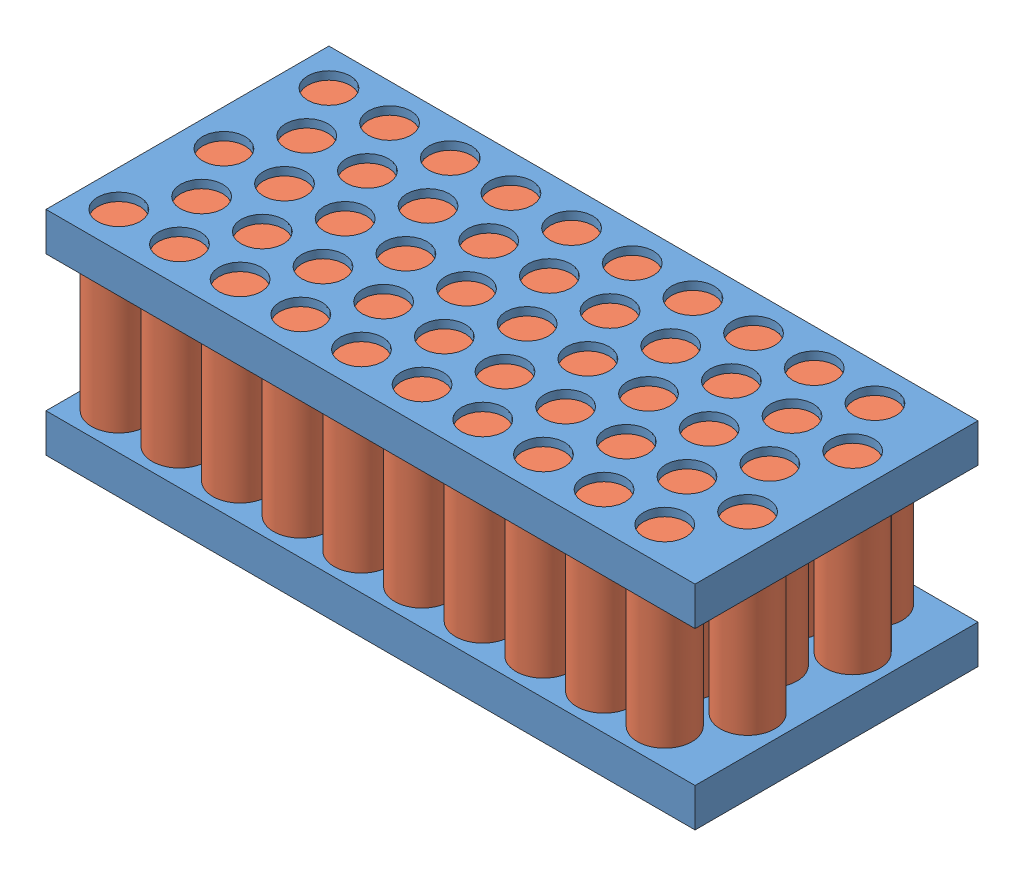
SolidWorks assembly Bank, configuration Default. Lengths in mm.
Overall size (214 70.2 93.28).
52 component instances, 2 part files, 153 mates.
Components (placement in the parent):
- EggCrate-1: EggCrate [Default] at origin size (214 12.7 93.28)
- 18650-1: 18650 [Default] at (180 10 0) x (0 0 -1) z (-1 0 0) size (18 65 18)
- 18650-2: 18650 [Default] at (160 10 0) x (0 0 -1) z (-1 0 0) size (18 65 18)
- 18650-3: 18650 [Default] at (140 10 0) x (0 0 -1) z (-1 0 0) size (18 65 18)
- 18650-4: 18650 [Default] at (120 10 0) x (0 0 -1) z (-1 0 0) size (18 65 18)
- 18650-5: 18650 [Default] at (100 10 0) x (0 0 -1) z (-1 0 0) size (18 65 18)
- 18650-6: 18650 [Default] at (80 10 0) x (0 0 -1) z (-1 0 0) size (18 65 18)
- 18650-7: 18650 [Default] at (60 10 0) x (0 0 -1) z (-1 0 0) size (18 65 18)
- 18650-8: 18650 [Default] at (40 10 0) x (0 0 -1) z (-1 0 0) size (18 65 18)
- 18650-9: 18650 [Default] at (20 10 0) x (0 0 -1) z (-1 0 0) size (18 65 18)
- 18650-10: 18650 [Default] at (0 10 0) x (0 0 -1) z (-1 0 0) size (18 65 18)
- 18650-11: 18650 [Default] at (10 10 -17.3205) x (0 0 -1) z (-1 0 0) size (18 65 18)
- 18650-12: 18650 [Default] at (30 10 -17.3205) x (0 0 -1) z (-1 0 0) size (18 65 18)
- 18650-13: 18650 [Default] at (50 10 -17.3205) x (0 0 -1) z (-1 0 0) size (18 65 18)
- 18650-14: 18650 [Default] at (70 10 -17.3205) x (0 0 -1) z (-1 0 0) size (18 65 18)
- 18650-15: 18650 [Default] at (90 10 -17.3205) x (0 0 -1) z (-1 0 0) size (18 65 18)
- 18650-16: 18650 [Default] at (110 10 -17.3205) x (0 0 -1) z (-1 0 0) size (18 65 18)
- 18650-17: 18650 [Default] at (130 10 -17.3205) x (0 0 -1) z (-1 0 0) size (18 65 18)
- 18650-18: 18650 [Default] at (150 10 -17.3205) x (0 0 -1) z (-1 0 0) size (18 65 18)
- 18650-19: 18650 [Default] at (170 10 -17.3205) x (0 0 -1) z (-1 0 0) size (18 65 18)
- 18650-20: 18650 [Default] at (190 10 -17.3205) x (0 0 -1) z (-1 0 0) size (18 65 18)
- 18650-21: 18650 [Default] at (0 10 -34.641) x (0 0 -1) z (-1 0 0) size (18 65 18)
- 18650-22: 18650 [Default] at (20 10 -34.641) x (0 0 -1) z (-1 0 0) size (18 65 18)
- 18650-23: 18650 [Default] at (40 10 -34.641) x (0 0 -1) z (-1 0 0) size (18 65 18)
- 18650-24: 18650 [Default] at (60 10 -34.641) x (0 0 -1) z (-1 0 0) size (18 65 18)
- 18650-25: 18650 [Default] at (80 10 -34.641) x (0 0 -1) z (-1 0 0) size (18 65 18)
- 18650-26: 18650 [Default] at (100 10 -34.641) x (0 0 -1) z (-1 0 0) size (18 65 18)
- 18650-27: 18650 [Default] at (120 10 -34.641) x (0 0 -1) z (-1 0 0) size (18 65 18)
- 18650-28: 18650 [Default] at (140 10 -34.641) x (0 0 -1) z (-1 0 0) size (18 65 18)
- 18650-29: 18650 [Default] at (160 10 -34.641) x (0 0 -1) z (-1 0 0) size (18 65 18)
- 18650-30: 18650 [Default] at (180 10 -34.641) x (0 0 -1) z (-1 0 0) size (18 65 18)
- 18650-31: 18650 [Default] at (10 10 -51.9615) x (0 0 -1) z (-1 0 0) size (18 65 18)
- 18650-32: 18650 [Default] at (30 10 -51.9615) x (0 0 -1) z (-1 0 0) size (18 65 18)
- 18650-33: 18650 [Default] at (50 10 -51.9615) x (0 0 -1) z (-1 0 0) size (18 65 18)
- 18650-34: 18650 [Default] at (70 10 -51.9615) x (0 0 -1) z (-1 0 0) size (18 65 18)
- 18650-35: 18650 [Default] at (90 10 -51.9615) x (0 0 -1) z (-1 0 0) size (18 65 18)
- 18650-36: 18650 [Default] at (110 10 -51.9615) x (0 0 -1) z (-1 0 0) size (18 65 18)
- 18650-37: 18650 [Default] at (130 10 -51.9615) x (0 0 -1) z (-1 0 0) size (18 65 18)
- 18650-38: 18650 [Default] at (150 10 -51.9615) x (0 0 -1) z (-1 0 0) size (18 65 18)
- 18650-39: 18650 [Default] at (170 10 -51.9615) x (0 0 -1) z (-1 0 0) size (18 65 18)
- 18650-40: 18650 [Default] at (190 10 -51.9615) x (0 0 -1) z (-1 0 0) size (18 65 18)
- 18650-41: 18650 [Default] at (180 10 -69.282) x (0 0 -1) z (-1 0 0) size (18 65 18)
- 18650-42: 18650 [Default] at (160 10 -69.282) x (0 0 -1) z (-1 0 0) size (18 65 18)
- 18650-43: 18650 [Default] at (140 10 -69.282) x (0 0 -1) z (-1 0 0) size (18 65 18)
- 18650-44: 18650 [Default] at (120 10 -69.282) x (0 0 -1) z (-1 0 0) size (18 65 18)
- 18650-45: 18650 [Default] at (100 10 -69.282) x (0 0 -1) z (-1 0 0) size (18 65 18)
- 18650-46: 18650 [Default] at (80 10 -69.282) x (0 0 -1) z (-1 0 0) size (18 65 18)
- 18650-47: 18650 [Default] at (60 10 -69.282) x (0 0 -1) z (-1 0 0) size (18 65 18)
- 18650-48: 18650 [Default] at (40 10 -69.282) x (0 0 -1) z (-1 0 0) size (18 65 18)
- 18650-49: 18650 [Default] at (20 10 -69.282) x (0 0 -1) z (-1 0 0) size (18 65 18)
- 18650-50: 18650 [Default] at (0 10 -69.282) x (0 0 -1) z (-1 0 0) size (18 65 18)
- EggCrate-2: EggCrate [Default] at (0 -44.8 -69.282) x (1 0 0) z (0 0 -1) size (214 12.7 93.28)
Mates (geometry in assembly coordinates):
- Coincident1: coincident anti-aligned: plane of EggCrate-1 through (180 10 0) normal (0 -1 0); plane of 18650-1 through (180 10 0) normal (0 1 0)
- Concentric1: concentric anti-aligned: cylinder of EggCrate-1 through (180 10 0) axis (0 -1 0) radius 9; cylinder of 18650-1 through (180 -55 0) axis (0 1 0) radius 9
- Parallel1: parallel anti-aligned: plane of 18650-1 through (180 10 0) normal (-1 0 0); plane of assembly through (0 0 0) normal (1 0 0)
- Coincident5: coincident anti-aligned: plane of EggCrate-1 through (180 10 0) normal (0 -1 0); plane of 18650-2 through (160 10 0) normal (0 1 0)
- Parallel2: parallel anti-aligned: plane of 18650-2 through (160 10 0) normal (-1 0 0); plane of assembly through (0 0 0) normal (1 0 0)
- Concentric2: concentric anti-aligned: cylinder of EggCrate-1 through (160 10 0) axis (0 -1 0) radius 9; cylinder of 18650-2 through (160 -55 0) axis (0 1 0) radius 9
- Coincident6: coincident anti-aligned: plane of EggCrate-1 through (180 10 0) normal (0 -1 0); plane of 18650-3 through (140 10 0) normal (0 1 0)
- Concentric3: concentric anti-aligned: cylinder of EggCrate-1 through (140 10 0) axis (0 -1 0) radius 9; cylinder of 18650-3 through (140 -55 0) axis (0 1 0) radius 9
- Parallel3: parallel anti-aligned: plane of 18650-3 through (140 10 0) normal (-1 0 0); plane of assembly through (0 0 0) normal (1 0 0)
- Coincident7: coincident anti-aligned: plane of EggCrate-1 through (180 10 0) normal (0 -1 0); plane of 18650-4 through (120 10 0) normal (0 1 0)
- Concentric4: concentric anti-aligned: cylinder of EggCrate-1 through (120 10 0) axis (0 -1 0) radius 9; cylinder of 18650-4 through (120 -55 0) axis (0 1 0) radius 9
- Parallel4: parallel anti-aligned: plane of 18650-4 through (120 10 0) normal (-1 0 0); plane of assembly through (0 0 0) normal (1 0 0)
- Coincident8: coincident anti-aligned: plane of EggCrate-1 through (180 10 0) normal (0 -1 0); plane of 18650-5 through (100 10 0) normal (0 1 0)
- Concentric5: concentric anti-aligned: cylinder of EggCrate-1 through (100 10 0) axis (0 -1 0) radius 9; cylinder of 18650-5 through (100 -55 0) axis (0 1 0) radius 9
- Parallel5: parallel anti-aligned: plane of 18650-5 through (100 10 0) normal (-1 0 0); plane of assembly through (0 0 0) normal (1 0 0)
- Coincident9: coincident anti-aligned: plane of EggCrate-1 through (180 10 0) normal (0 -1 0); plane of 18650-6 through (80 10 0) normal (0 1 0)
- Concentric6: concentric anti-aligned: cylinder of EggCrate-1 through (80 10 0) axis (0 -1 0) radius 9; cylinder of 18650-6 through (80 -55 0) axis (0 1 0) radius 9
- Parallel6: parallel anti-aligned: plane of 18650-6 through (80 10 0) normal (-1 0 0); plane of assembly through (0 0 0) normal (1 0 0)
- Coincident10: coincident anti-aligned: plane of EggCrate-1 through (180 10 0) normal (0 -1 0); plane of 18650-7 through (60 10 0) normal (0 1 0)
- Concentric7: concentric anti-aligned: cylinder of EggCrate-1 through (60 10 0) axis (0 -1 0) radius 9; cylinder of 18650-7 through (60 -55 0) axis (0 1 0) radius 9
- Parallel7: parallel anti-aligned: plane of 18650-7 through (60 10 0) normal (-1 0 0); plane of assembly through (0 0 0) normal (1 0 0)
- Coincident11: coincident anti-aligned: plane of EggCrate-1 through (180 10 0) normal (0 -1 0); plane of 18650-8 through (40 10 0) normal (0 1 0)
- Concentric8: concentric anti-aligned: cylinder of EggCrate-1 through (40 10 0) axis (0 -1 0) radius 9; cylinder of 18650-8 through (40 -55 0) axis (0 1 0) radius 9
- Parallel8: parallel anti-aligned: plane of 18650-8 through (40 10 0) normal (-1 0 0); plane of assembly through (0 0 0) normal (1 0 0)
- Coincident12: coincident anti-aligned: plane of EggCrate-1 through (180 10 0) normal (0 -1 0); plane of 18650-9 through (20 10 0) normal (0 1 0)
- Concentric9: concentric anti-aligned: cylinder of EggCrate-1 through (20 10 0) axis (0 -1 0) radius 9; cylinder of 18650-9 through (20 -55 0) axis (0 1 0) radius 9
- Parallel9: parallel anti-aligned: plane of 18650-9 through (20 10 0) normal (-1 0 0); plane of assembly through (0 0 0) normal (1 0 0)
- Coincident13: coincident anti-aligned: plane of EggCrate-1 through (180 10 0) normal (0 -1 0); plane of 18650-10 through (0 10 0) normal (0 1 0)
- Concentric10: concentric anti-aligned: cylinder of EggCrate-1 through (0 10 0) axis (0 -1 0) radius 9; cylinder of 18650-10 through (0 -55 0) axis (0 1 0) radius 9
- Parallel10: parallel anti-aligned: plane of 18650-10 through (0 10 0) normal (-1 0 0); plane of assembly through (0 0 0) normal (1 0 0)
- Coincident14: coincident anti-aligned: plane of EggCrate-1 through (180 10 0) normal (0 -1 0); plane of 18650-11 through (10 10 -17.3205) normal (0 1 0)
- Concentric11: concentric anti-aligned: cylinder of EggCrate-1 through (10 10 -17.3205) axis (0 -1 0) radius 9; cylinder of 18650-11 through (10 -55 -17.3205) axis (0 1 0) radius 9
- Parallel11: parallel anti-aligned: plane of 18650-11 through (10 10 -17.3205) normal (-1 0 0); plane of assembly through (0 0 0) normal (1 0 0)
- Coincident15: coincident anti-aligned: plane of EggCrate-1 through (180 10 0) normal (0 -1 0); plane of 18650-12 through (30 10 -17.3205) normal (0 1 0)
- Concentric12: concentric anti-aligned: cylinder of EggCrate-1 through (30 10 -17.3205) axis (0 -1 0) radius 9; cylinder of 18650-12 through (30 -55 -17.3205) axis (0 1 0) radius 9
- Parallel12: parallel anti-aligned: plane of 18650-12 through (30 10 -17.3205) normal (-1 0 0); plane of assembly through (0 0 0) normal (1 0 0)
- Coincident16: coincident anti-aligned: plane of EggCrate-1 through (180 10 0) normal (0 -1 0); plane of 18650-13 through (50 10 -17.3205) normal (0 1 0)
- Concentric13: concentric anti-aligned: cylinder of EggCrate-1 through (50 10 -17.3205) axis (0 -1 0) radius 9; cylinder of 18650-13 through (50 -55 -17.3205) axis (0 1 0) radius 9
- Parallel13: parallel anti-aligned: plane of 18650-13 through (50 10 -17.3205) normal (-1 0 0); plane of assembly through (0 0 0) normal (1 0 0)
- Coincident17: coincident anti-aligned: plane of EggCrate-1 through (180 10 0) normal (0 -1 0); plane of 18650-14 through (70 10 -17.3205) normal (0 1 0)
- Concentric14: concentric anti-aligned: cylinder of EggCrate-1 through (70 10 -17.3205) axis (0 -1 0) radius 9; cylinder of 18650-14 through (70 -55 -17.3205) axis (0 1 0) radius 9
- Parallel14: parallel anti-aligned: plane of 18650-14 through (70 10 -17.3205) normal (-1 0 0); plane of assembly through (0 0 0) normal (1 0 0)
- Coincident18: coincident anti-aligned: plane of EggCrate-1 through (180 10 0) normal (0 -1 0); plane of 18650-15 through (90 10 -17.3205) normal (0 1 0)
- Concentric15: concentric anti-aligned: cylinder of EggCrate-1 through (90 10 -17.3205) axis (0 -1 0) radius 9; cylinder of 18650-15 through (90 -55 -17.3205) axis (0 1 0) radius 9
- Parallel15: parallel anti-aligned: plane of 18650-15 through (90 10 -17.3205) normal (-1 0 0); plane of assembly through (0 0 0) normal (1 0 0)
- Coincident19: coincident anti-aligned: plane of EggCrate-1 through (180 10 0) normal (0 -1 0); plane of 18650-16 through (110 10 -17.3205) normal (0 1 0)
- Concentric16: concentric anti-aligned: cylinder of EggCrate-1 through (110 10 -17.3205) axis (0 -1 0) radius 9; cylinder of 18650-16 through (110 -55 -17.3205) axis (0 1 0) radius 9
- Parallel16: parallel anti-aligned: plane of 18650-16 through (110 10 -17.3205) normal (-1 0 0); plane of assembly through (0 0 0) normal (1 0 0)
- Coincident20: coincident anti-aligned: plane of EggCrate-1 through (180 10 0) normal (0 -1 0); plane of 18650-17 through (130 10 -17.3205) normal (0 1 0)
- Concentric17: concentric anti-aligned: cylinder of EggCrate-1 through (130 10 -17.3205) axis (0 -1 0) radius 9; cylinder of 18650-17 through (130 -55 -17.3205) axis (0 1 0) radius 9
- Parallel17: parallel anti-aligned: plane of 18650-17 through (130 10 -17.3205) normal (-1 0 0); plane of assembly through (0 0 0) normal (1 0 0)
- Coincident21: coincident anti-aligned: plane of EggCrate-1 through (180 10 0) normal (0 -1 0); plane of 18650-18 through (150 10 -17.3205) normal (0 1 0)
- Concentric18: concentric anti-aligned: cylinder of EggCrate-1 through (150 10 -17.3205) axis (0 -1 0) radius 9; cylinder of 18650-18 through (150 -55 -17.3205) axis (0 1 0) radius 9
- Parallel18: parallel anti-aligned: plane of 18650-18 through (150 10 -17.3205) normal (-1 0 0); plane of assembly through (0 0 0) normal (1 0 0)
- Coincident22: coincident anti-aligned: plane of EggCrate-1 through (180 10 0) normal (0 -1 0); plane of 18650-19 through (170 10 -17.3205) normal (0 1 0)
- Concentric19: concentric anti-aligned: cylinder of EggCrate-1 through (170 10 -17.3205) axis (0 -1 0) radius 9; cylinder of 18650-19 through (170 -55 -17.3205) axis (0 1 0) radius 9
- Parallel19: parallel anti-aligned: plane of 18650-19 through (170 10 -17.3205) normal (-1 0 0); plane of assembly through (0 0 0) normal (1 0 0)
- Coincident23: coincident anti-aligned: plane of EggCrate-1 through (180 10 0) normal (0 -1 0); plane of 18650-20 through (190 10 -17.3205) normal (0 1 0)
- Concentric20: concentric anti-aligned: cylinder of EggCrate-1 through (190 10 -17.3205) axis (0 -1 0) radius 9; cylinder of 18650-20 through (190 -55 -17.3205) axis (0 1 0) radius 9
- Parallel20: parallel anti-aligned: plane of 18650-20 through (190 10 -17.3205) normal (-1 0 0); plane of assembly through (0 0 0) normal (1 0 0)
- Coincident24: coincident anti-aligned: plane of EggCrate-1 through (180 10 0) normal (0 -1 0); plane of 18650-21 through (0 10 -34.641) normal (0 1 0)
- Concentric21: concentric anti-aligned: cylinder of EggCrate-1 through (0 10 -34.641) axis (0 -1 0) radius 9; cylinder of 18650-21 through (0 -55 -34.641) axis (0 1 0) radius 9
- Parallel21: parallel anti-aligned: plane of 18650-21 through (0 10 -34.641) normal (-1 0 0); plane of assembly through (0 0 0) normal (1 0 0)
- Coincident25: coincident anti-aligned: plane of EggCrate-1 through (180 10 0) normal (0 -1 0); plane of 18650-22 through (20 10 -34.641) normal (0 1 0)
- Concentric22: concentric anti-aligned: cylinder of EggCrate-1 through (20 10 -34.641) axis (0 -1 0) radius 9; cylinder of 18650-22 through (20 -55 -34.641) axis (0 1 0) radius 9
- Parallel22: parallel anti-aligned: plane of 18650-22 through (20 10 -34.641) normal (-1 0 0); plane of assembly through (0 0 0) normal (1 0 0)
- Coincident26: coincident anti-aligned: plane of EggCrate-1 through (180 10 0) normal (0 -1 0); plane of 18650-23 through (40 10 -34.641) normal (0 1 0)
- Concentric23: concentric anti-aligned: cylinder of EggCrate-1 through (40 10 -34.641) axis (0 -1 0) radius 9; cylinder of 18650-23 through (40 -55 -34.641) axis (0 1 0) radius 9
- Parallel23: parallel anti-aligned: plane of 18650-23 through (40 10 -34.641) normal (-1 0 0); plane of assembly through (0 0 0) normal (1 0 0)
- Coincident27: coincident anti-aligned: plane of EggCrate-1 through (180 10 0) normal (0 -1 0); plane of 18650-24 through (60 10 -34.641) normal (0 1 0)
- Concentric24: concentric anti-aligned: cylinder of EggCrate-1 through (60 10 -34.641) axis (0 -1 0) radius 9; cylinder of 18650-24 through (60 -55 -34.641) axis (0 1 0) radius 9
- Parallel24: parallel anti-aligned: plane of 18650-24 through (60 10 -34.641) normal (-1 0 0); plane of assembly through (0 0 0) normal (1 0 0)
- Coincident28: coincident anti-aligned: plane of EggCrate-1 through (180 10 0) normal (0 -1 0); plane of 18650-25 through (80 10 -34.641) normal (0 1 0)
- Concentric25: concentric anti-aligned: cylinder of EggCrate-1 through (80 10 -34.641) axis (0 -1 0) radius 9; cylinder of 18650-25 through (80 -55 -34.641) axis (0 1 0) radius 9
- Parallel25: parallel anti-aligned: plane of 18650-25 through (80 10 -34.641) normal (-1 0 0); plane of assembly through (0 0 0) normal (1 0 0)
- Coincident29: coincident anti-aligned: plane of EggCrate-1 through (180 10 0) normal (0 -1 0); plane of 18650-26 through (100 10 -34.641) normal (0 1 0)
- Concentric26: concentric anti-aligned: cylinder of EggCrate-1 through (100 10 -34.641) axis (0 -1 0) radius 9; cylinder of 18650-26 through (100 -55 -34.641) axis (0 1 0) radius 9
- Parallel26: parallel anti-aligned: plane of 18650-26 through (100 10 -34.641) normal (-1 0 0); plane of assembly through (0 0 0) normal (1 0 0)
- Coincident30: coincident anti-aligned: plane of EggCrate-1 through (180 10 0) normal (0 -1 0); plane of 18650-27 through (120 10 -34.641) normal (0 1 0)
- Concentric27: concentric anti-aligned: cylinder of EggCrate-1 through (120 10 -34.641) axis (0 -1 0) radius 9; cylinder of 18650-27 through (120 -55 -34.641) axis (0 1 0) radius 9
- Parallel27: parallel anti-aligned: plane of 18650-27 through (120 10 -34.641) normal (-1 0 0); plane of assembly through (0 0 0) normal (1 0 0)
- Coincident31: coincident anti-aligned: plane of EggCrate-1 through (180 10 0) normal (0 -1 0); plane of 18650-28 through (140 10 -34.641) normal (0 1 0)
- Concentric28: concentric anti-aligned: cylinder of EggCrate-1 through (140 10 -34.641) axis (0 -1 0) radius 9; cylinder of 18650-28 through (140 -55 -34.641) axis (0 1 0) radius 9
- Parallel28: parallel anti-aligned: plane of 18650-28 through (140 10 -34.641) normal (-1 0 0); plane of assembly through (0 0 0) normal (1 0 0)
- Coincident32: coincident anti-aligned: plane of EggCrate-1 through (180 10 0) normal (0 -1 0); plane of 18650-29 through (160 10 -34.641) normal (0 1 0)
- Concentric29: concentric anti-aligned: cylinder of EggCrate-1 through (160 10 -34.641) axis (0 -1 0) radius 9; cylinder of 18650-29 through (160 -55 -34.641) axis (0 1 0) radius 9
- Parallel29: parallel anti-aligned: plane of 18650-29 through (160 10 -34.641) normal (-1 0 0); plane of assembly through (0 0 0) normal (1 0 0)
- Coincident33: coincident anti-aligned: plane of EggCrate-1 through (180 10 0) normal (0 -1 0); plane of 18650-30 through (180 10 -34.641) normal (0 1 0)
- Concentric30: concentric anti-aligned: cylinder of EggCrate-1 through (180 10 -34.641) axis (0 -1 0) radius 9; cylinder of 18650-30 through (180 -55 -34.641) axis (0 1 0) radius 9
- Parallel30: parallel anti-aligned: plane of 18650-30 through (180 10 -34.641) normal (-1 0 0); plane of assembly through (0 0 0) normal (1 0 0)
- Coincident34: coincident anti-aligned: plane of EggCrate-1 through (180 10 0) normal (0 -1 0); plane of 18650-31 through (10 10 -51.9615) normal (0 1 0)
- Concentric31: concentric anti-aligned: cylinder of EggCrate-1 through (10 10 -51.9615) axis (0 -1 0) radius 9; cylinder of 18650-31 through (10 -55 -51.9615) axis (0 1 0) radius 9
- Parallel31: parallel anti-aligned: plane of 18650-31 through (10 10 -51.9615) normal (-1 0 0); plane of assembly through (0 0 0) normal (1 0 0)
- Coincident35: coincident anti-aligned: plane of EggCrate-1 through (180 10 0) normal (0 -1 0); plane of 18650-32 through (30 10 -51.9615) normal (0 1 0)
- Concentric32: concentric anti-aligned: cylinder of EggCrate-1 through (30 10 -51.9615) axis (0 -1 0) radius 9; cylinder of 18650-32 through (30 -55 -51.9615) axis (0 1 0) radius 9
- Parallel32: parallel anti-aligned: plane of 18650-32 through (30 10 -51.9615) normal (-1 0 0); plane of assembly through (0 0 0) normal (1 0 0)
- Coincident36: coincident anti-aligned: plane of EggCrate-1 through (180 10 0) normal (0 -1 0); plane of 18650-33 through (50 10 -51.9615) normal (0 1 0)
- Concentric33: concentric anti-aligned: cylinder of EggCrate-1 through (50 10 -51.9615) axis (0 -1 0) radius 9; cylinder of 18650-33 through (50 -55 -51.9615) axis (0 1 0) radius 9
- Parallel33: parallel anti-aligned: plane of 18650-33 through (50 10 -51.9615) normal (-1 0 0); plane of assembly through (0 0 0) normal (1 0 0)
- Coincident37: coincident anti-aligned: plane of EggCrate-1 through (180 10 0) normal (0 -1 0); plane of 18650-34 through (70 10 -51.9615) normal (0 1 0)
- Concentric34: concentric anti-aligned: cylinder of EggCrate-1 through (70 10 -51.9615) axis (0 -1 0) radius 9; cylinder of 18650-34 through (70 -55 -51.9615) axis (0 1 0) radius 9
- Parallel34: parallel anti-aligned: plane of 18650-34 through (70 10 -51.9615) normal (-1 0 0); plane of assembly through (0 0 0) normal (1 0 0)
- Coincident38: coincident anti-aligned: plane of EggCrate-1 through (180 10 0) normal (0 -1 0); plane of 18650-35 through (90 10 -51.9615) normal (0 1 0)
- Concentric35: concentric anti-aligned: cylinder of EggCrate-1 through (90 10 -51.9615) axis (0 -1 0) radius 9; cylinder of 18650-35 through (90 -55 -51.9615) axis (0 1 0) radius 9
- Parallel35: parallel anti-aligned: plane of 18650-35 through (90 10 -51.9615) normal (-1 0 0); plane of assembly through (0 0 0) normal (1 0 0)
- Coincident39: coincident anti-aligned: plane of EggCrate-1 through (180 10 0) normal (0 -1 0); plane of 18650-36 through (110 10 -51.9615) normal (0 1 0)
- Concentric36: concentric anti-aligned: cylinder of EggCrate-1 through (110 10 -51.9615) axis (0 -1 0) radius 9; cylinder of 18650-36 through (110 -55 -51.9615) axis (0 1 0) radius 9
- Parallel36: parallel anti-aligned: plane of 18650-36 through (110 10 -51.9615) normal (-1 0 0); plane of assembly through (0 0 0) normal (1 0 0)
- Coincident40: coincident anti-aligned: plane of EggCrate-1 through (180 10 0) normal (0 -1 0); plane of 18650-37 through (130 10 -51.9615) normal (0 1 0)
- Concentric37: concentric anti-aligned: cylinder of EggCrate-1 through (130 10 -51.9615) axis (0 -1 0) radius 9; cylinder of 18650-37 through (130 -55 -51.9615) axis (0 1 0) radius 9
- Parallel37: parallel anti-aligned: plane of 18650-37 through (130 10 -51.9615) normal (-1 0 0); plane of assembly through (0 0 0) normal (1 0 0)
- Coincident41: coincident anti-aligned: plane of EggCrate-1 through (180 10 0) normal (0 -1 0); plane of 18650-38 through (150 10 -51.9615) normal (0 1 0)
- Concentric38: concentric anti-aligned: cylinder of EggCrate-1 through (150 10 -51.9615) axis (0 -1 0) radius 9; cylinder of 18650-38 through (150 -55 -51.9615) axis (0 1 0) radius 9
- Parallel38: parallel anti-aligned: plane of 18650-38 through (150 10 -51.9615) normal (-1 0 0); plane of assembly through (0 0 0) normal (1 0 0)
- Coincident42: coincident anti-aligned: plane of EggCrate-1 through (180 10 0) normal (0 -1 0); plane of 18650-39 through (170 10 -51.9615) normal (0 1 0)
- Concentric39: concentric anti-aligned: cylinder of EggCrate-1 through (170 10 -51.9615) axis (0 -1 0) radius 9; cylinder of 18650-39 through (170 -55 -51.9615) axis (0 1 0) radius 9
- Parallel39: parallel anti-aligned: plane of 18650-39 through (170 10 -51.9615) normal (-1 0 0); plane of assembly through (0 0 0) normal (1 0 0)
- Coincident43: coincident anti-aligned: plane of EggCrate-1 through (180 10 0) normal (0 -1 0); plane of 18650-40 through (190 10 -51.9615) normal (0 1 0)
- Concentric40: concentric anti-aligned: cylinder of EggCrate-1 through (190 10 -51.9615) axis (0 -1 0) radius 9; cylinder of 18650-40 through (190 -55 -51.9615) axis (0 1 0) radius 9
- Parallel40: parallel anti-aligned: plane of 18650-40 through (190 10 -51.9615) normal (-1 0 0); plane of assembly through (0 0 0) normal (1 0 0)
- Coincident44: coincident anti-aligned: plane of EggCrate-1 through (180 10 0) normal (0 -1 0); plane of 18650-41 through (180 10 -69.282) normal (0 1 0)
- Concentric41: concentric anti-aligned: cylinder of EggCrate-1 through (180 10 -69.282) axis (0 -1 0) radius 9; cylinder of 18650-41 through (180 -55 -69.282) axis (0 1 0) radius 9
- Parallel41: parallel anti-aligned: plane of 18650-41 through (180 10 -69.282) normal (-1 0 0); plane of assembly through (0 0 0) normal (1 0 0)
- Coincident45: coincident anti-aligned: plane of EggCrate-1 through (180 10 0) normal (0 -1 0); plane of 18650-42 through (160 10 -69.282) normal (0 1 0)
- Concentric42: concentric anti-aligned: cylinder of EggCrate-1 through (160 10 -69.282) axis (0 -1 0) radius 9; cylinder of 18650-42 through (160 -55 -69.282) axis (0 1 0) radius 9
- Parallel42: parallel anti-aligned: plane of 18650-42 through (160 10 -69.282) normal (-1 0 0); plane of assembly through (0 0 0) normal (1 0 0)
- Coincident46: coincident anti-aligned: plane of EggCrate-1 through (180 10 0) normal (0 -1 0); plane of 18650-43 through (140 10 -69.282) normal (0 1 0)
- Concentric43: concentric anti-aligned: cylinder of EggCrate-1 through (140 10 -69.282) axis (0 -1 0) radius 9; cylinder of 18650-43 through (140 -55 -69.282) axis (0 1 0) radius 9
- Parallel43: parallel anti-aligned: plane of 18650-43 through (140 10 -69.282) normal (-1 0 0); plane of assembly through (0 0 0) normal (1 0 0)
- Coincident47: coincident anti-aligned: plane of EggCrate-1 through (180 10 0) normal (0 -1 0); plane of 18650-44 through (120 10 -69.282) normal (0 1 0)
- Concentric44: concentric anti-aligned: cylinder of EggCrate-1 through (120 10 -69.282) axis (0 -1 0) radius 9; cylinder of 18650-44 through (120 -55 -69.282) axis (0 1 0) radius 9
- Parallel44: parallel anti-aligned: plane of 18650-44 through (120 10 -69.282) normal (-1 0 0); plane of assembly through (0 0 0) normal (1 0 0)
- Coincident48: coincident anti-aligned: plane of EggCrate-1 through (180 10 0) normal (0 -1 0); plane of 18650-45 through (100 10 -69.282) normal (0 1 0)
- Concentric45: concentric anti-aligned: cylinder of EggCrate-1 through (100 10 -69.282) axis (0 -1 0) radius 9; cylinder of 18650-45 through (100 -55 -69.282) axis (0 1 0) radius 9
- Parallel45: parallel anti-aligned: plane of 18650-45 through (100 10 -69.282) normal (-1 0 0); plane of assembly through (0 0 0) normal (1 0 0)
- Coincident49: coincident anti-aligned: plane of EggCrate-1 through (180 10 0) normal (0 -1 0); plane of 18650-46 through (80 10 -69.282) normal (0 1 0)
- Concentric46: concentric anti-aligned: cylinder of EggCrate-1 through (80 10 -69.282) axis (0 -1 0) radius 9; cylinder of 18650-46 through (80 -55 -69.282) axis (0 1 0) radius 9
- Parallel46: parallel anti-aligned: plane of 18650-46 through (80 10 -69.282) normal (-1 0 0); plane of assembly through (0 0 0) normal (1 0 0)
- Coincident50: coincident anti-aligned: plane of EggCrate-1 through (180 10 0) normal (0 -1 0); plane of 18650-47 through (60 10 -69.282) normal (0 1 0)
- Concentric47: concentric anti-aligned: cylinder of EggCrate-1 through (60 10 -69.282) axis (0 -1 0) radius 9; cylinder of 18650-47 through (60 -55 -69.282) axis (0 1 0) radius 9
- Parallel47: parallel anti-aligned: plane of 18650-47 through (60 10 -69.282) normal (-1 0 0); plane of assembly through (0 0 0) normal (1 0 0)
- Coincident51: coincident anti-aligned: plane of EggCrate-1 through (180 10 0) normal (0 -1 0); plane of 18650-48 through (40 10 -69.282) normal (0 1 0)
- Concentric48: concentric anti-aligned: cylinder of EggCrate-1 through (40 10 -69.282) axis (0 -1 0) radius 9; cylinder of 18650-48 through (40 -55 -69.282) axis (0 1 0) radius 9
- Parallel48: parallel anti-aligned: plane of 18650-48 through (40 10 -69.282) normal (-1 0 0); plane of assembly through (0 0 0) normal (1 0 0)
- Coincident52: coincident anti-aligned: plane of EggCrate-1 through (180 10 0) normal (0 -1 0); plane of 18650-49 through (20 10 -69.282) normal (0 1 0)
- Concentric49: concentric anti-aligned: cylinder of EggCrate-1 through (20 10 -69.282) axis (0 -1 0) radius 9; cylinder of 18650-49 through (20 -55 -69.282) axis (0 1 0) radius 9
- Parallel49: parallel anti-aligned: plane of 18650-49 through (20 10 -69.282) normal (-1 0 0); plane of assembly through (0 0 0) normal (1 0 0)
- Coincident53: coincident anti-aligned: plane of EggCrate-1 through (180 10 0) normal (0 -1 0); plane of 18650-50 through (0 10 -69.282) normal (0 1 0)
- Concentric50: concentric anti-aligned: cylinder of EggCrate-1 through (0 10 -69.282) axis (0 -1 0) radius 9; cylinder of 18650-50 through (0 -55 -69.282) axis (0 1 0) radius 9
- Parallel50: parallel anti-aligned: plane of 18650-50 through (0 10 -69.282) normal (-1 0 0); plane of assembly through (0 0 0) normal (1 0 0)
- Coincident54: coincident anti-aligned: circle of 18650-1; plane of EggCrate-2 through (180 -54.8 0) normal (0 1 0)
- Concentric52: concentric aligned: cylinder of 18650-1 through (180 -55 0) axis (0 1 0) radius 9; cylinder of EggCrate-2 through (180 -54.8 0) axis (0 1 0) radius 9
- Coincident56: coincident aligned: plane of EggCrate-1 through (202 12.7 12) normal (1 0 0); plane of EggCrate-2 through (202 -57.5 -81.282) normal (1 0 0)
